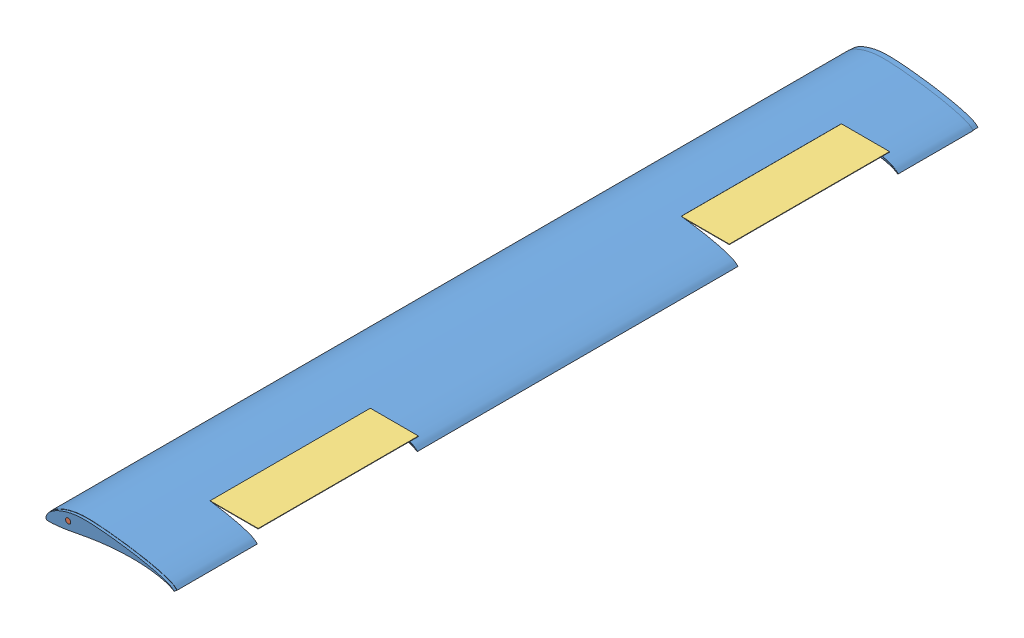
SolidWorks assembly Assem1, configuration Default. Lengths in mm.
Overall size (450.61 115.15 2508).
4 component instances, 3 part files, 9 mates.
Components (placement in the parent):
- WING-1: WING [Default] at (1200.506 1195.7941 1956.557) size (450.61 115.15 2508)
- SPAR-1: SPAR [Default] at (870.506 1220.7941 706.557) size (16 16 2500)
- AILERON-1: AILERON [Default] at (1055.506 1238.9484 2448.557) x (0 0 1) z (0 -1 0) size (500 150 1.5)
- AILERON-2: AILERON [Default] at (1025.4984 1240.8915 1448.557) x (0 0 -1) z (0 1 0) size (500 150 1.5)
Mates (geometry in assembly coordinates):
- Concentric1: concentric: cylinder of WING-1 through (870.506 1220.7941 698.557) axis (0 0 1) radius 8; cylinder of SPAR-1 through (870.506 1220.7941 3206.557) axis (0 0 -1) radius 8
- Coincident1: coincident: circle of WING-1; plane of SPAR-1 through (870.506 1220.7941 3206.557) normal (0 0 1)
- Coincident2: coincident: plane of WING-1 through (1055.506 1141.7941 2448.557) normal (1 0 0); plane of AILERON-1 through (1055.506 1237.4484 2448.557) normal (-1 0 0)
- Coincident3: coincident: plane of WING-1 through (1055.506 1141.7941 2448.557) normal (0 0 1); plane of AILERON-1 through (1055.506 1237.4484 2448.557) normal (0 0 -1)
- Lock1: lock: unknown of WING-1; unknown of AILERON-1
- Coincident4: coincident: plane of WING-1 through (1025.4984 1141.7941 1448.557) normal (1 0 0); plane of AILERON-2 through (1025.4984 1242.3915 1448.557) normal (-1 0 0)
- Coincident5: coincident: plane of WING-1 through (1025.4984 1141.7941 948.557) normal (0 0 1); plane of AILERON-2 through (1025.4984 1242.3915 948.557) normal (0 0 -1)
- Lock2: lock: unknown of WING-1; unknown of AILERON-2
- Lock3: lock: unknown of WING-1; unknown of SPAR-1
